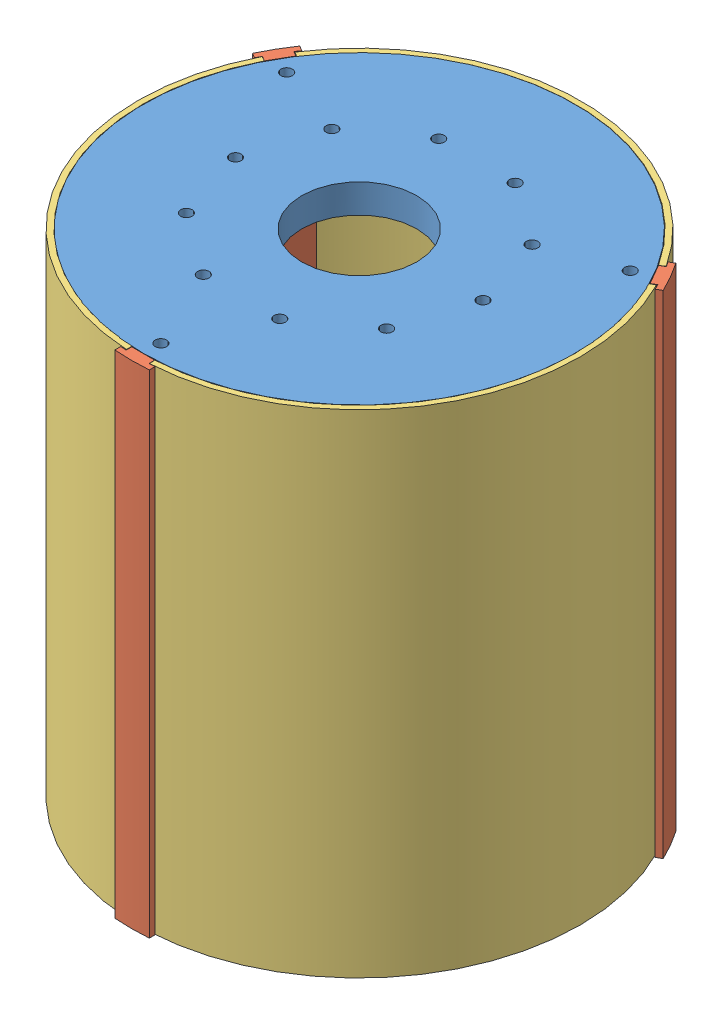
SolidWorks assembly CouplingAndShell, configuration Default. Lengths in mm.
Overall size (106.05 85.5 103.45).
7 component instances, 3 part files, 5 mates.
Components (placement in the parent):
- Coupling-1: Coupling [Default] at (-150.9016 153.1618 -6.2345) size (75 5 75)
- Brace-2: Brace [Default] at (-150.9016 153.1618 -6.1553) size (75 85.5 77)
- Brace-5: Brace [Default] at (-150.833 153.1618 -6.2741) x (-0.5 0 -0.866025) z (0.866025 0 -0.5) size (75 85.5 77)
- Brace-6: Brace [Default] at (-150.9702 153.1618 -6.2741) x (-0.5 0 0.866025) z (-0.866025 0 -0.5) size (75 85.5 77)
- Shell-9: Shell [Default] at (-150.9098 153.1618 -6.1549) x (-0.499797 0 0.866142) z (-0.866142 0 -0.499797) size (64.49 85.5 18.02)
- Shell-10: Shell [Default] at (-150.8285 153.1618 -6.2672) x (1 0 -0.000234) z (0.000234 0 1) size (64.49 85.5 18.02)
- Shell-11: Shell [Default] at (-150.9665 153.1618 -6.2814) x (-0.500203 0 -0.865908) z (0.865908 0 -0.500203) size (64.49 85.5 18.02)
Mates (geometry in assembly coordinates):
- Concentric13: concentric anti-aligned: circle of Coupling-1; circle of Brace-2
- Coincident3: coincident aligned: plane of Coupling-1 through (-150.9016 153.1618 -6.2345) normal (0 1 0); plane of Brace-2 through (-150.9016 153.1618 -6.1553) normal (0 1 0)
- Coincident5: coincident aligned: line of Brace-2 through (-148.9016 91.6618 31.2913) axis (0 1 0); line of Shell-9 through (-148.9016 67.6618 31.2913) axis (0 1 0)
- Coincident14: coincident aligned: plane of Coupling-1 through (-150.9016 153.1618 -6.2345) normal (0 1 0); plane of Shell-9 through (-150.9098 153.1618 -6.1549) normal (0 1 0)
- Coincident15: coincident: point of Brace-6; point of Shell-9
